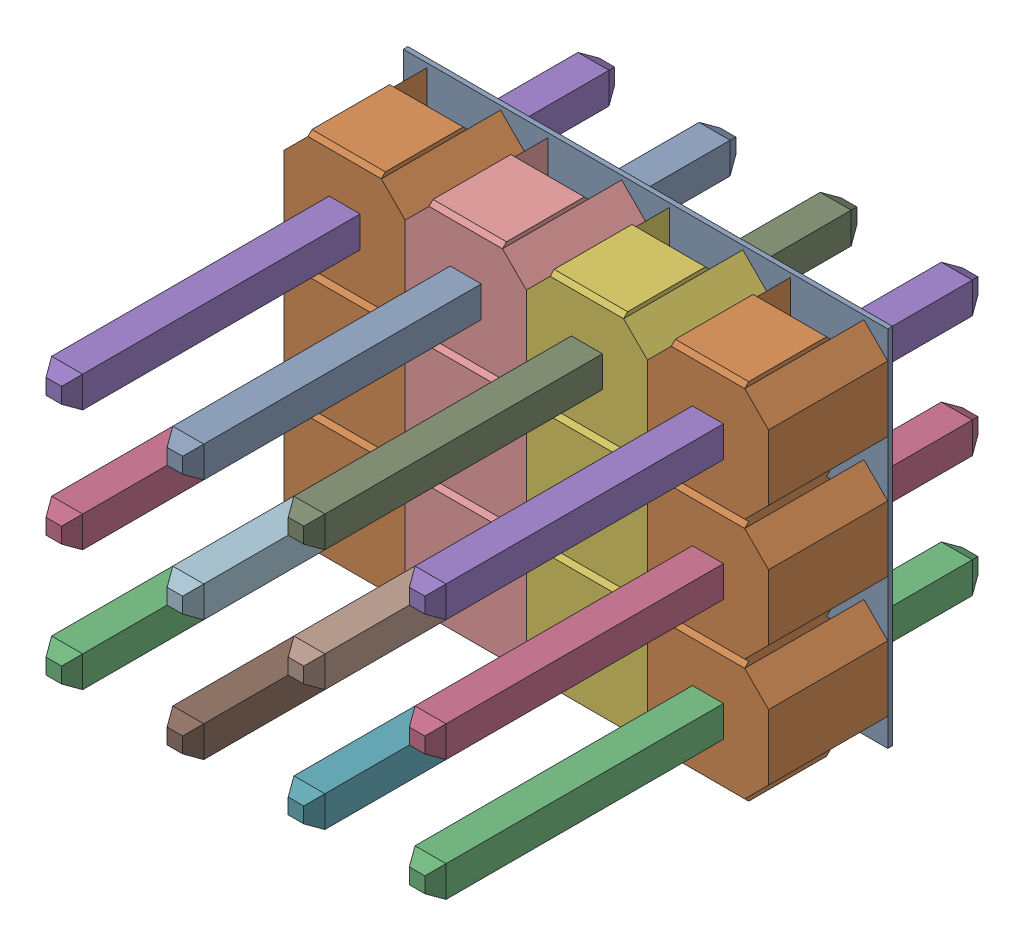
SolidWorks assembly 254-3X4-1, configuration 默认. Lengths in mm.
Overall size (10.16 7.62 11.6).
11 component instances, 2 part files, 0 mates.
Components (placement in the parent):
- PCB-1: PCB [默认] at (-5.04 -3.81 0) size (10.16 7.62 11.6)
  - Board-1: Board [默认] at origin size (10.16 7.62 0.1)
    - Open CASCADE STEP translator 6.8 6.1.1-1: Open CASCADE STEP translator 6.8 6.1.1 [默认] at (0 0 -0.0965) size (10.16 7.62 0.1)
  - Z_RST3-1: Z_RST3 [默认] at origin size (2.54 7.62 11.6)
    - DS1021-1x3SF11-1: DS1021-1x3SF11 [默认] at (8.8901 1.2699 0) x (0 1 0) z (0 0 1) size (7.62 2.54 11.6)
  - Z_RST2-1: Z_RST2 [默认] at origin size (2.54 7.62 11.6)
    - DS1021-1x3SF11-1: DS1021-1x3SF11 [默认] at (6.3501 1.2699 0) x (0 1 0) z (0 0 1) size (7.62 2.54 11.6)
  - Z_RST1-1: Z_RST1 [默认] at origin size (2.54 7.62 11.6)
    - DS1021-1x3SF11-1: DS1021-1x3SF11 [默认] at (3.8101 1.2699 0) x (0 1 0) z (0 0 1) size (7.62 2.54 11.6)
  - Z_RST-1: Z_RST [默认] at origin size (2.54 7.62 11.6)
    - DS1021-1x3SF11-1: DS1021-1x3SF11 [默认] at (1.2701 1.2699 0) x (0 1 0) z (0 0 1) size (7.62 2.54 11.6)
